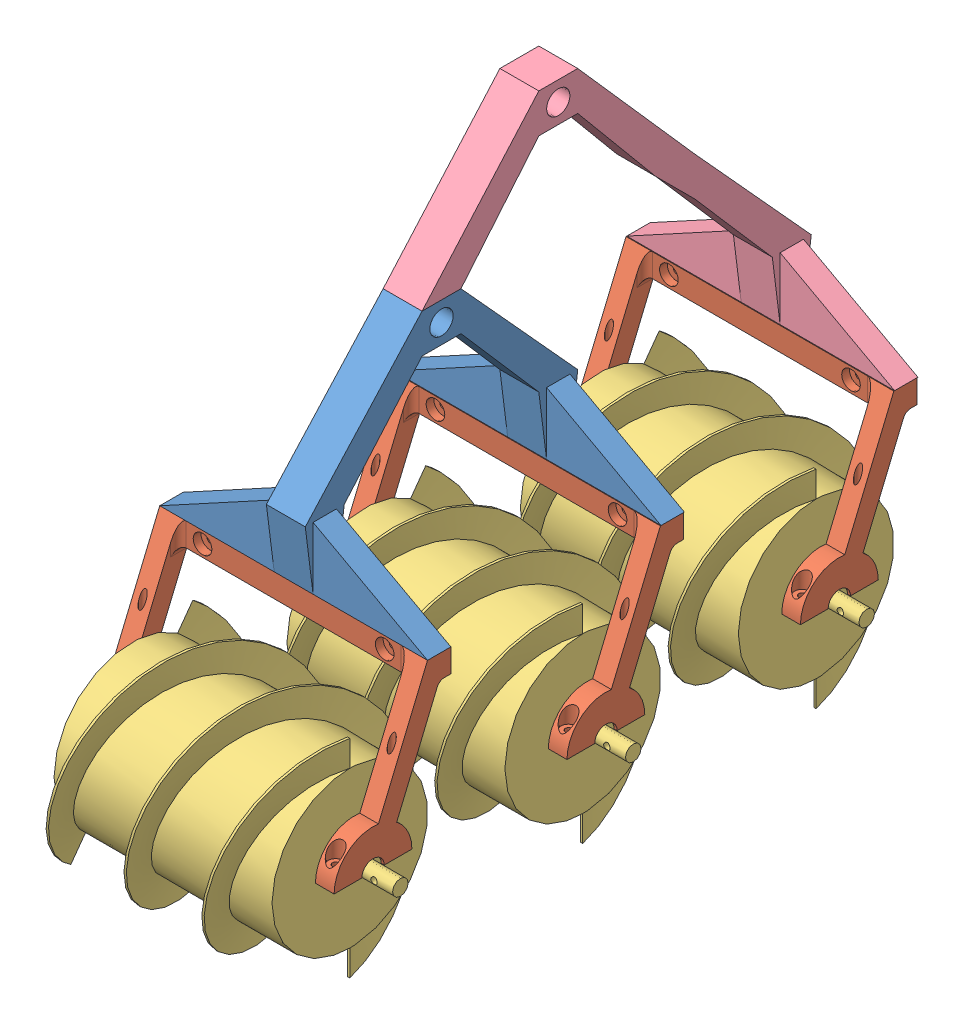
SolidWorks assembly Assem4, configuration Default. Lengths in mm.
Overall size (189.58 374.46 432.88).
12 component instances, 4 part files, 4 mates.
Components (placement in the parent):
- Rocker_ASSM-1: Rocker_ASSM [Default] at (219.9815 -31.2349 -252.3043) size (189.58 289.46 282.93)
  - Rocker_0.2-1: Rocker_0.2 [Default] at (90.7291 81.5764 127.5436) size (172 122.5 175)
  - Right_Side_Wheel-1: Right_Side_Wheel [Default] at (-44.7546 -109.1572 354.9679) x (0 0 -1) z (1 0 0) size (133.34 166.96 189.58)
    - GSL_Feet_Right_GSL12-1: GSL_Feet_Right_GSL12 [Default] at (92.4243 183.2337 135.4838) size (133.3 166.65 172)
    - HGSL2_CC-1: HGSL2_CC [Default] at (34.9243 90.7337 66.5638) size (133.34 133.91 174.84)
  - Right_Side_Wheel-2: Right_Side_Wheel [Default] at (-44.7546 -109.1572 205.3767) x (0 0 -1) z (1 0 0) size (133.34 166.96 189.58)
    - GSL_Feet_Right_GSL12-1: GSL_Feet_Right_GSL12 [Default] at (92.4243 183.2337 135.4838) size (133.3 166.65 172)
    - HGSL2_CC-1: HGSL2_CC [Default] at (34.9243 90.7337 66.5638) size (133.34 133.91 174.84)
- Bogie_0.2-1: Bogie_0.2 [Default] at (310.7106 50.3415 -274.7606) size (172 207.5 250)
- Right_Side_Wheel-1: Right_Side_Wheel [Default] at (175.2268 -140.3921 -196.8756) x (0 0 -1) z (1 0 0) size (133.34 166.96 189.58)
  - GSL_Feet_Right_GSL12-1: GSL_Feet_Right_GSL12 [Default] at (92.4243 183.2337 135.4838) size (133.3 166.65 172)
  - HGSL2_CC-1: HGSL2_CC [Default] at (34.9243 90.7337 66.5638) size (133.34 133.91 174.84)
Mates (geometry in assembly coordinates):
- Coincident8: coincident: line of Rocker_ASSM-1/Rocker_0.2-1 through (323.2106 172.8415 -37.2606) axis (-1 0 0); line of Bogie_0.2-1 through (298.2106 172.8415 -37.2606) axis (1 0 0)
- Coincident9: coincident: line of Rocker_ASSM-1/Rocker_0.2-1 through (323.2106 172.8415 -62.2606) axis (0 0 1); line of Bogie_0.2-1 through (323.2106 172.8415 -62.2606) axis (0 0 1)
- Coincident10: coincident: plane of Bogie_0.2-1 through (310.7106 50.3415 -274.7606) normal (0 -1 0); plane of Right_Side_Wheel-1/GSL_Feet_Right_GSL12-1 through (396.7106 50.3415 -281.7999) normal (0 1 0)
- Coincident11: coincident: line of Bogie_0.2-1 through (396.7106 50.3415 -282.2606) axis (0 0 1); plane of Right_Side_Wheel-1/GSL_Feet_Right_GSL12-1 through (396.7106 42.8415 -289.2999) normal (1 0 0)
